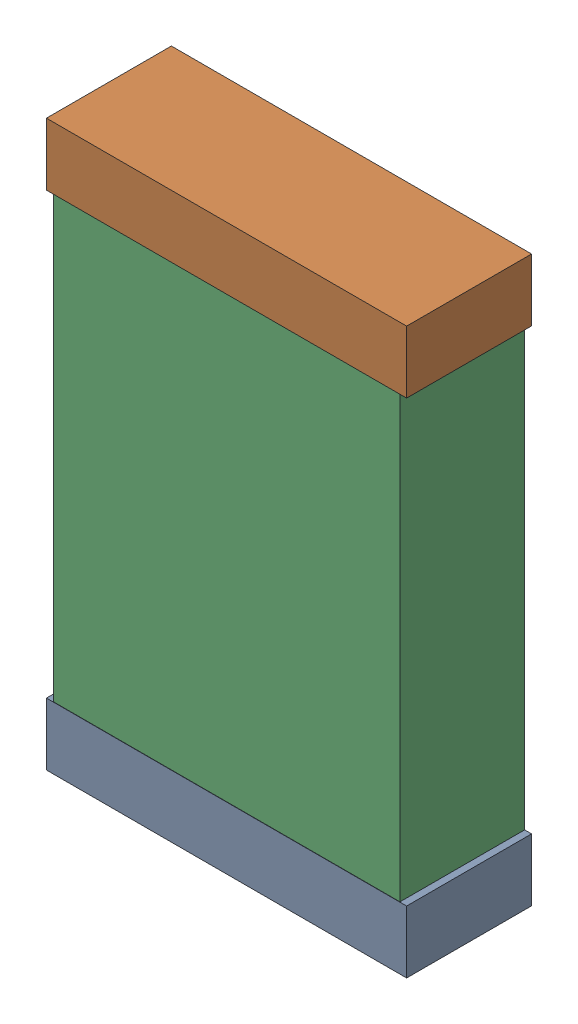
SolidWorks assembly C45, configuration Default. Lengths in mm.
Overall size (1.3 2.04 0.45).
6 component instances, 2 part files, 0 mates.
Components (placement in the parent):
- 740902240-1: 740902240 [Default] at (74.9292 21.3736 0) size (1.3 0.23 0.45)
  - Extruded_35-1: Extruded_35 [Default] at origin size (1.3 0.23 0.45)
- 740902240-2: 740902240 [Default] at (74.9292 23.1861 0) size (1.3 0.23 0.45)
  - Extruded_35-1: Extruded_35 [Default] at origin size (1.3 0.23 0.45)
- 740904480-1: 740904480 [Default] at (74.9292 22.2736 0) size (1.25 2 0.45)
  - Extruded_34-1: Extruded_34 [Default] at origin size (1.25 2 0.45)
